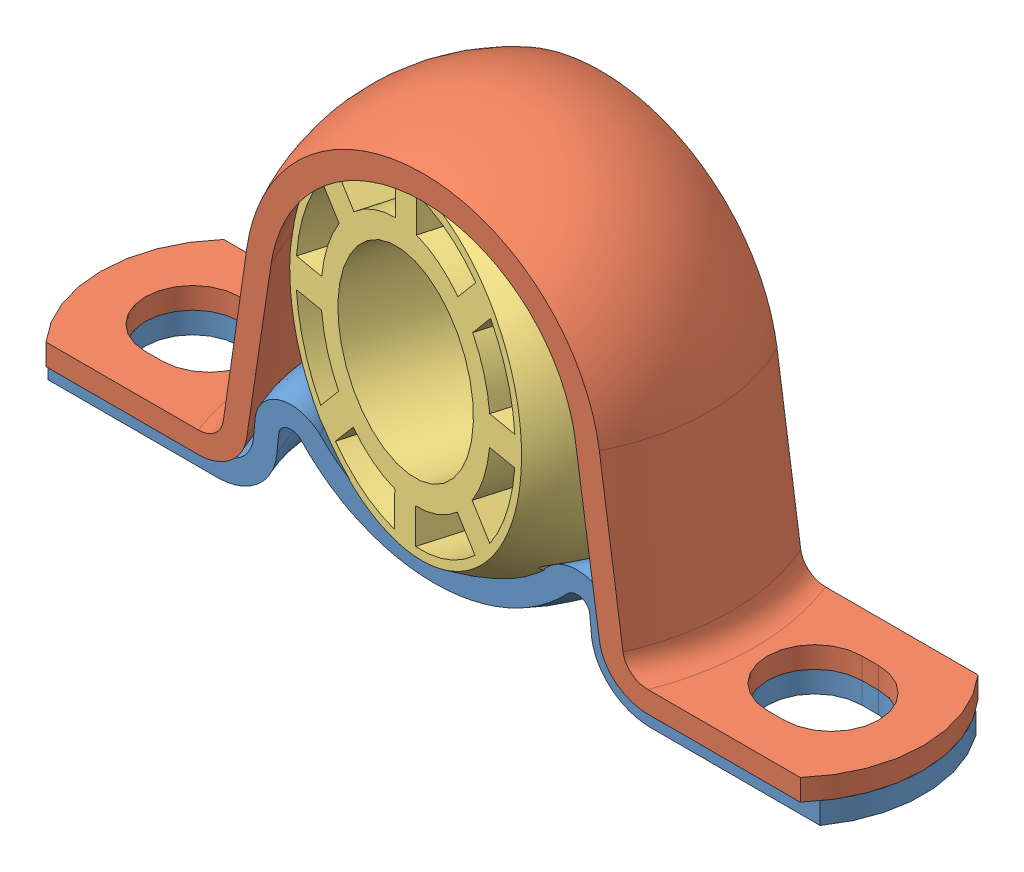
SolidWorks assembly PillowBlockBearing, configuration Default. Lengths in mm.
Overall size (58.75 37.06 32.69).
3 component instances, 3 part files, 4 mates.
Components (placement in the parent):
- PillowBlockBearing_Base-1: PillowBlockBearing_Base [Default] at origin size (58.75 8.17 17.61)
- PillowBlockBearing_Strap-1: PillowBlockBearing_Strap [Default] at (0 1.524 0) size (58.75 27.15 27.42)
- PillowBlockBearing_N8-1: PillowBlockBearing_N8 [Default] at (0 14.224 0) x (0.650907 0.750273 0.115804) z (-0.725571 0.6597 -0.195812) size (25.39 25.4 25.63)
Mates (geometry in assembly coordinates):
- Coincident1: coincident anti-aligned: plane of PillowBlockBearing_Base-1 through (16.4409 1.524 0) normal (0 1 0); plane of PillowBlockBearing_Strap-1 through (50.8 1.524 0) normal (0 -1 0)
- Concentric1: concentric anti-aligned: cylinder of PillowBlockBearing_Base-1 through (21.6281 0 0) axis (0 1 0) radius 3.3782; cylinder of PillowBlockBearing_Strap-1 through (21.6281 28.448 0) axis (0 -1 0) radius 3.3782
- Concentric2: concentric anti-aligned: cylinder of PillowBlockBearing_Base-1 through (-21.6281 0 0) axis (0 1 0) radius 3.3782; cylinder of PillowBlockBearing_Strap-1 through (-21.6281 28.448 0) axis (0 -1 0) radius 3.3782
- Coincident2: coincident: point of PillowBlockBearing_Strap-1; point of PillowBlockBearing_N8-1
